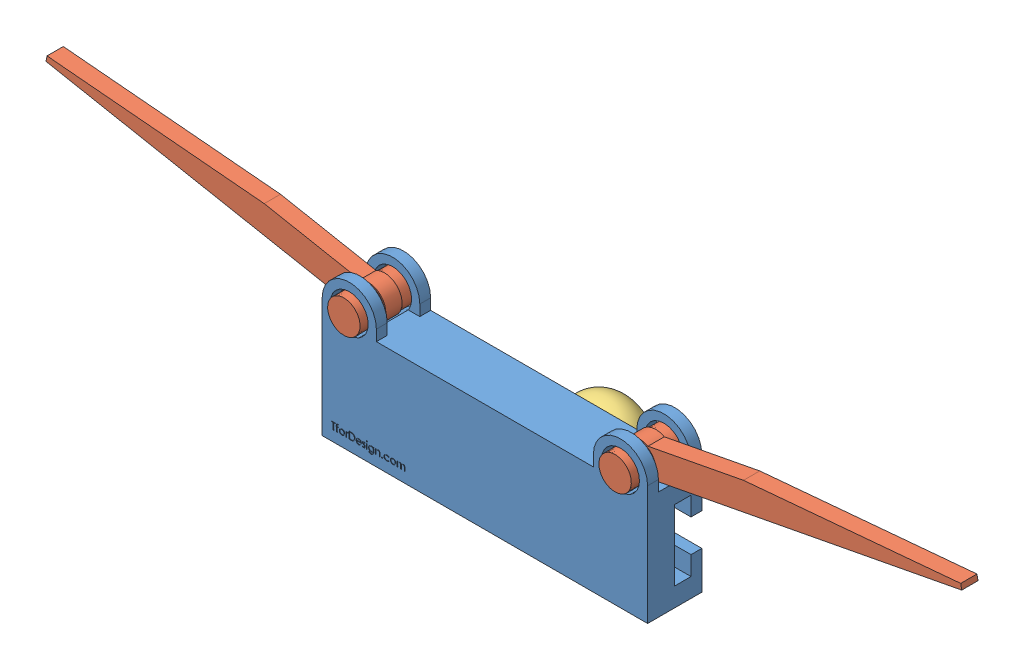
SolidWorks assembly lec43-collision-intrference-detection, configuration Default. Lengths in mm.
Overall size (169.09 36.88 20.93).
5 component instances, 4 part files, 9 mates.
Components (placement in the parent):
- Main Body_15-1: Main Body_15 [Default] at (23.8141 35.8796 34.8255) size (60 27 10)
- Antenna-1: Antenna [Default] at (48.8141 47.8796 39.8255) x (0.982296 0.187336 0) z (-0.187336 0.982296 0) size (63.25 12 6.5)
- Knob-1: Knob [Default] at (30.9713 35.8796 39.3255) x (-0.598689 -0.800982 0) z (0.800982 -0.598689 0) size (14.93 14.43 14.93)
- Antenna-2: Antenna [Default] at (-1.1859 47.8796 39.8255) x (-0.982296 0.187336 0) z (0.187336 0.982296 0) size (63.25 12 6.5)
- Side Cap_15-2: Side Cap_15 [Default] at (-6.1859 36.1106 35.5075) x (0 0 1) z (1 0 0) size (5.59 13.46 1.27)
Mates (geometry in assembly coordinates):
- Concentric1: concentric anti-aligned: circle of Main Body_15-1; circle of Antenna-2
- Width1: width anti-aligned: plane of Main Body_15-1 through (53.8141 45.8796 36.8255) normal (0 0 1); plane of Main Body_15-1 through (53.8141 45.8796 42.8255) normal (0 0 -1); plane of Antenna-2 through (-1.1859 47.8796 38.3255) normal (0 0 -1); plane of Antenna-2 through (-1.1859 47.8796 41.3255) normal (0 0 1)
- Concentric2: concentric anti-aligned: circle of Main Body_15-1; circle of Antenna-1
- Width2: width anti-aligned: plane of Main Body_15-1 through (53.8141 45.8796 36.8255) normal (0 0 1); plane of Main Body_15-1 through (53.8141 45.8796 42.8255) normal (0 0 -1); plane of Antenna-1 through (48.8141 47.8796 38.3255) normal (0 0 -1); plane of Antenna-1 through (48.8141 47.8796 41.3255) normal (0 0 1)
- Symmetric1: symmetric aligned: plane of Main Body_15-1 through (23.8141 35.8796 34.8255) normal (1 0 0); plane of Antenna-1 through (49.2825 45.4239 39.8255) normal (0.187336 -0.982296 0); plane of Antenna-2 through (-1.6542 45.4239 39.8255) normal (-0.187336 -0.982296 0)
- Width3: width: plane of Main Body_15-1 through (-6.1859 42.3796 34.8255) normal (0 -1 0); plane of Main Body_15-1 through (-6.1859 29.3796 34.8255) normal (0 1 0); cylinder of Knob-1 through (30.9713 35.8796 25.5755) axis (0 0 -1) radius 6
- Width4: width anti-aligned: plane of Main Body_15-1 through (-6.1859 35.8796 36.8255) normal (0 0 1); plane of Main Body_15-1 through (-6.1859 35.8796 39.8255) normal (0 0 -1); plane of Knob-1 through (26.1654 39.4717 37.3255) normal (0 0 -1); plane of Knob-1 through (30.9713 35.8796 39.3255) normal (0 0 1)
- Coincident17: coincident anti-aligned: line of Main Body_15-1 through (-6.1859 29.3796 39.8255) axis (0 0 -1); line of Side Cap_15-2 through (-6.1859 29.3796 34.5014) axis (0 0 1)
- Coincident20: coincident: line of Main Body_15-1 through (-6.1859 29.3796 39.8255) axis (0 1 0); point of Side Cap_15-2
